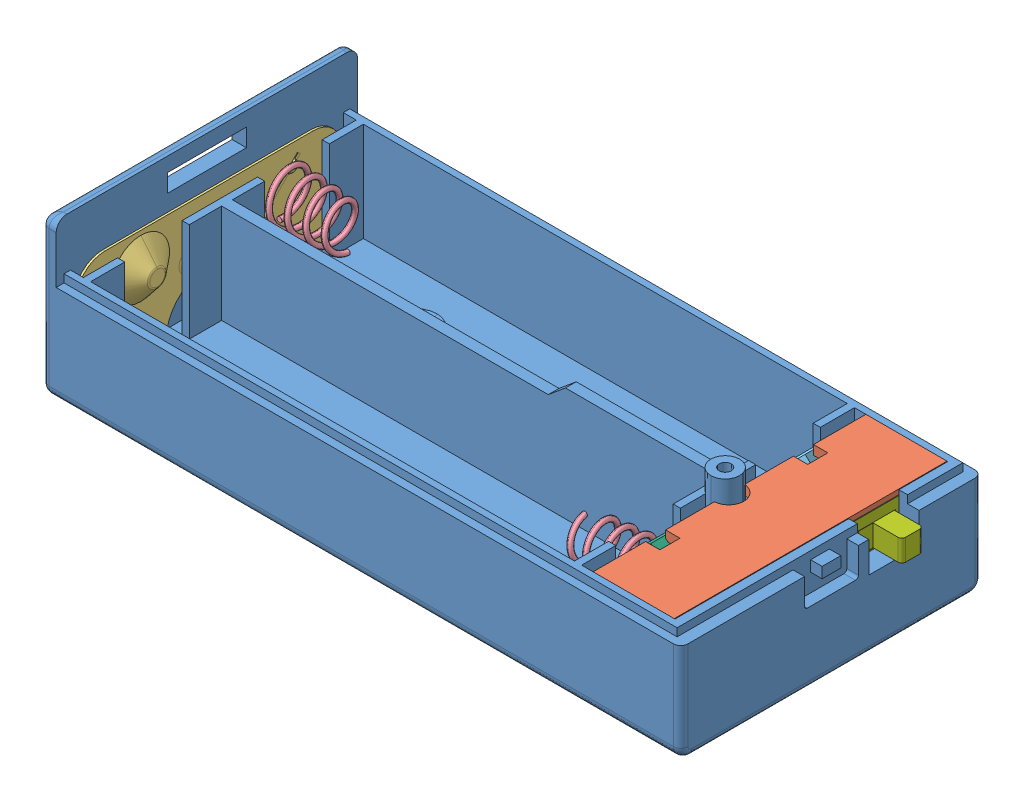
SolidWorks assembly 3.7V 2X 18650 BATTERY HOLDER WITH ON OFF SWITCH (1), configuration Default. Lengths in mm.
Overall size (90.2 22 42.01).
10 component instances, 8 part files, 0 mates.
Components (placement in the parent):
- 3.7V 2X 18650 BATTERY HOLDER WITH ON OFF SWITCH (1).STEP-1: 3.7V 2X 18650 BATTERY HOLDER WITH ON OFF SWITCH (1).STEP [Default] at origin size (90.8 22 42.01)
  - CASE, 3.7V 2X 18650 BATTERY HOLDER WITH ON OFF SWITCH.STEP-1: CASE, 3.7V 2X 18650 BATTERY HOLDER WITH ON OFF SWITCH.STEP [Default] at origin size (89 22 42.01)
  - SWITCH AND WIRING COVER, 3.7V 2X 18650 BATTERY HOLDER WITH ON OFF SWITCH.STEP-1: SWITCH AND WIRING COVER, 3.7V 2X 18650 BATTERY HOLDER WITH ON OFF SWITCH.STEP [Default] at (35.95 15 0) x (1 0 0) z (0 0 -1) size (11.3 3.7 38)
  - BATTERY CONDUCTION CLIP, 3.7V 2X 18650 BATTERY HOLDER WITH ON OFF SWITCH.STEP-1: BATTERY CONDUCTION CLIP, 3.7V 2X 18650 BATTERY HOLDER WITH ON OFF SWITCH.STEP [Default] at (-42.5 8.2 0) x (0 0 1) z (0 1 0) size (37 2.6 14)
  - SPRING, 3.7V 2X 18650 BATTERY HOLDER WITH ON OFF SWITCH.STEP-1: SPRING, 3.7V 2X 18650 BATTERY HOLDER WITH ON OFF SWITCH.STEP [Default] at (-37.0934 10.6 -9.5) x (0 0 -1) z (0 -1 0) size (7.33 10.2 7.44)
  - BATTERY CONDUCTION CLIP, POSITIVE TERMINAL, 3.7V 2X 18650 BATTERY HOLDER WITH ON OFF SWITCH.STEP-1: BATTERY CONDUCTION CLIP, POSITIVE TERMINAL, 3.7V 2X 18650 BATTERY HOLDER WITH ON OFF SWITCH.STEP [Default] at (30.1 7.7 -9.75) x (0 0 -1) z (0 1 0) size (15 6.6 13)
  - BATTERY CONDUCTION CLIP, NEGATIVE TERMINAL, 3.7V 2X 18650 BATTERY HOLDER WITH ON OFF SWITCH.STEP-1: BATTERY CONDUCTION CLIP, NEGATIVE TERMINAL, 3.7V 2X 18650 BATTERY HOLDER WITH ON OFF SWITCH.STEP [Default] at (30.1 7.7 9.75) x (0 0 -1) z (0 1 0) size (15 5.6 13)
  - SPRING, 3.7V 2X 18650 BATTERY HOLDER WITH ON OFF SWITCH.STEP-2: SPRING, 3.7V 2X 18650 BATTERY HOLDER WITH ON OFF SWITCH.STEP [Default] at (24.6934 9.6 9.75) x (0 0 -1) z (0 1 0) size (7.33 10.2 7.44)
  - SLIDE SWITCH SPDT, 3.7V 2X 18650 BATTERY HOLDER WITH ON OFF SWITCH_OFF.STEP-1: SLIDE SWITCH SPDT, 3.7V 2X 18650 BATTERY HOLDER WITH ON OFF SWITCH_OFF.STEP [Default] at (36.7 11.3 -8.7) x (0 0 -1) z (0 -1 0) size (19 12 6)
  - COVER, 3.7V 2X 18650 BATTERY HOLDER WITH ON OFF SWITCH.STEP-1: COVER, 3.7V 2X 18650 BATTERY HOLDER WITH ON OFF SWITCH.STEP [Default] at (1 22 0) x (1 0 0) z (0 0 -1) size (89.6 11.9 42) (hidden)
